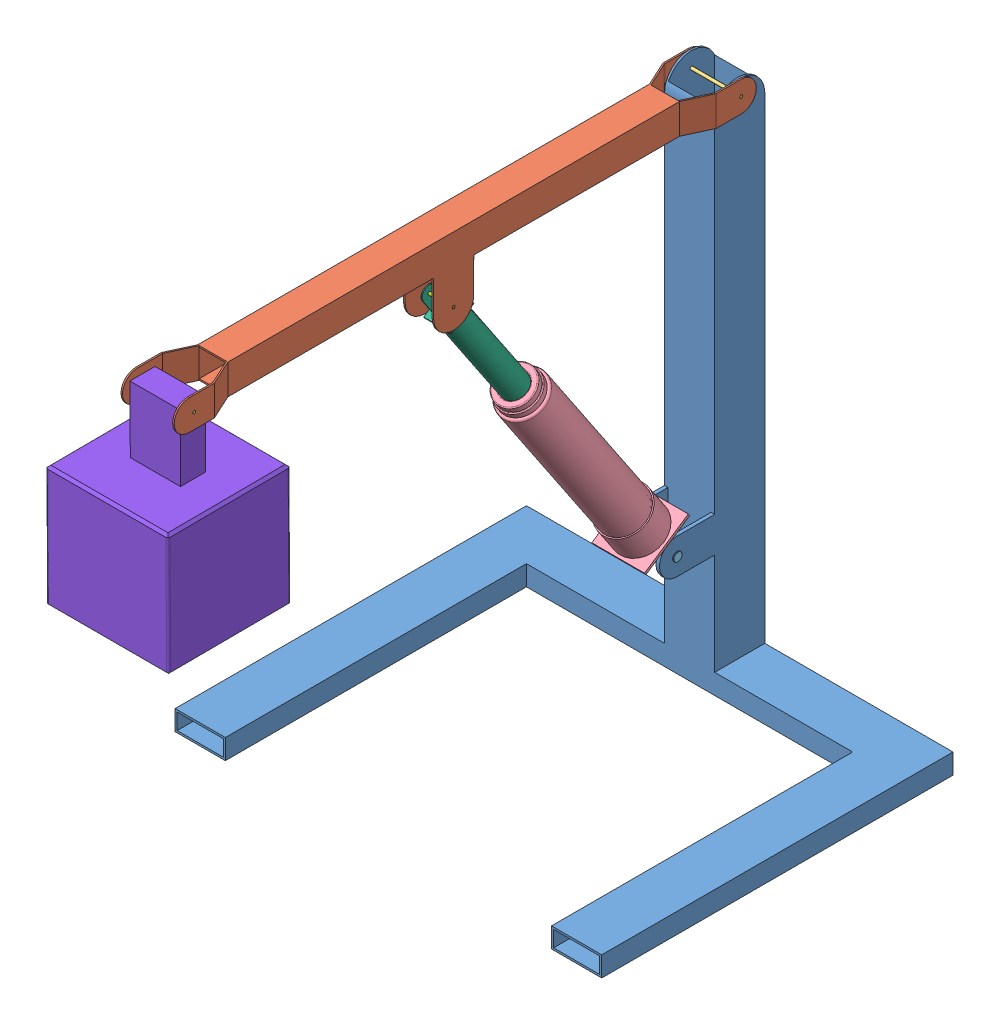
SolidWorks assembly Assem2, configuration Varsayılan. Lengths in mm.
Overall size (1700 2080.62 2523.58).
9 component instances, 8 part files, 16 mates.
Components (placement in the parent):
- BasePlate-1: BasePlate [Varsayılan] at (-60.2423 -835.2124 1480) size (1700 2080 1400)
- Boom-1: Boom [Varsayılan] at (-60.2423 1104.8423 1680) x (1 0 0) z (0 0.000273 1) size (212 340 2320)
- Pin-1: Pin [Varsayılan] at (-166.2423 1104.7876 1480) x (1 0 0) z (0 -0.113236 -0.993568) size (212 12 12)
- PistonAltmil-1: PistonAltmil [Varsayılan] at (-60.2423 457.2939 2279.2173) x (-1 0 0) z (0 0.830071 0.557658) size (210 210 1050)
- AltPim-1: AltPim [Varsayılan] at (-160.2423 -360.2124 1730) x (0 0 -1) z (1 0 0) size (35 35 204)
- PistonUstMil-1: PistonUstMil [Varsayılan] at (-60.2423 107.3905 2044.1451) x (1 0 0) z (0 -0.830071 -0.557658) size (108 108 991)
- Ustpin-1: Ustpin [Varsayılan] at (-120.2423 905.0884 2580.0547) x (0 -0.919913 -0.392121) z (1 0 0) size (12 12 120)
- mass-1: mass [Varsayılan] at (-60.2423 383.5596 3656.0508) x (1 0 0) z (0 -0.005471 0.999985) size (486.84 751.84 486.84)
- Pin-2: Pin [Varsayılan] at (-166.2423 1105.3838 3659.9999) size (212 12 12)
Mates (geometry in assembly coordinates):
- Eş Merkezli1: concentric aligned: cylinder of BasePlate-1 through (1839.7577 1104.7876 1480) axis (-1 0 0) radius 6; cylinder of Boom-1 through (43.7577 1104.7876 1480) axis (-1 0 0) radius 6
- Çakışık1: coincident anti-aligned: plane of BasePlate-1 through (-160.2423 1164.7876 1580) normal (-1 0 0); plane of Boom-1 through (-160.2423 1044.815 1580.0164) normal (1 0 0)
- Eş Merkezli2: concentric aligned: cylinder of Boom-1 through (43.7577 1104.7876 1480) axis (-1 0 0) radius 6; cylinder of Pin-1 through (45.7577 1104.7876 1480) axis (-1 0 0) radius 6
- Çakışık2: coincident aligned: plane of Boom-1 through (45.7577 1044.815 1580.0164) normal (1 0 0); plane of Pin-1 through (45.7577 1104.7876 1480) normal (1 0 0)
- Eş Merkezli3: concentric anti-aligned: cylinder of BasePlate-1 through (-160.2423 -360.2124 1730) axis (1 0 0) radius 15; cylinder of AltPim-1 through (39.7577 -360.2124 1730) axis (-1 0 0) radius 15
- Çakışık3: coincident anti-aligned: plane of BasePlate-1 through (39.7577 1164.7876 1580) normal (1 0 0); plane of AltPim-1 through (39.7577 -360.2124 1730) normal (-1 0 0)
- Eş Merkezli6: concentric aligned: cylinder of PistonAltmil-1 through (44.7577 -360.2124 1730) axis (-1 0 0) radius 15; cylinder of AltPim-1 through (39.7577 -360.2124 1730) axis (-1 0 0) radius 15
- Uzaklık2: distance = 86 mm anti-aligned: plane of PistonAltmil-1; plane of BasePlate-1 through (-146.2423 -450.2124 1580) normal (1 0 0)
- Eş Merkezli7: concentric anti-aligned: cylinder of Boom-1 through (-180.2423 905.0884 2580.0547) axis (1 0 0) radius 6; cylinder of Ustpin-1 through (-0.2423 905.0884 2580.0547) axis (-1 0 0) radius 6
- Çakışık10: coincident aligned: plane of Boom-1 through (-0.2423 1045.3892 3680.0163) normal (1 0 0); plane of Ustpin-1 through (-0.2423 905.0884 2580.0547) normal (1 0 0)
- Eş Merkezli10: concentric anti-aligned: cylinder of PistonAltmil-1 through (-60.2423 -663.3015 1526.3786) axis (0 0.830071 0.557658) radius 50; cylinder of PistonUstMil-1 through (-60.2423 842.0031 2537.6726) axis (0 -0.830071 -0.557658) radius 50
- Eş Merkezli11: concentric aligned: cylinder of PistonUstMil-1 through (9.7577 905.0884 2580.0547) axis (-1 0 0) radius 6; cylinder of Ustpin-1 through (-0.2423 905.0884 2580.0547) axis (-1 0 0) radius 6
- Eş Merkezli12: concentric anti-aligned: cylinder of Boom-1 through (-166.2423 1105.3838 3659.9999) axis (1 0 0) radius 6; cylinder of Pin-2 through (45.7577 1105.3838 3659.9999) axis (-1 0 0) radius 6
- Çakışık13: coincident aligned: plane of Boom-1 through (45.7577 1045.3619 3580.0163) normal (1 0 0); plane of Pin-2 through (45.7577 1105.3838 3659.9999) normal (1 0 0)
- Eş Merkezli13: concentric anti-aligned: cylinder of mass-1 through (-303.6598 1105.3838 3659.9999) axis (1 0 0) radius 6; cylinder of Pin-2 through (45.7577 1105.3838 3659.9999) axis (-1 0 0) radius 6
- Çakışık14: coincident anti-aligned: plane of Boom-1 through (39.7577 1045.3619 3580.0163) normal (-1 0 0); plane of mass-1 through (39.7577 1120.11 3710.0812) normal (1 0 0)
